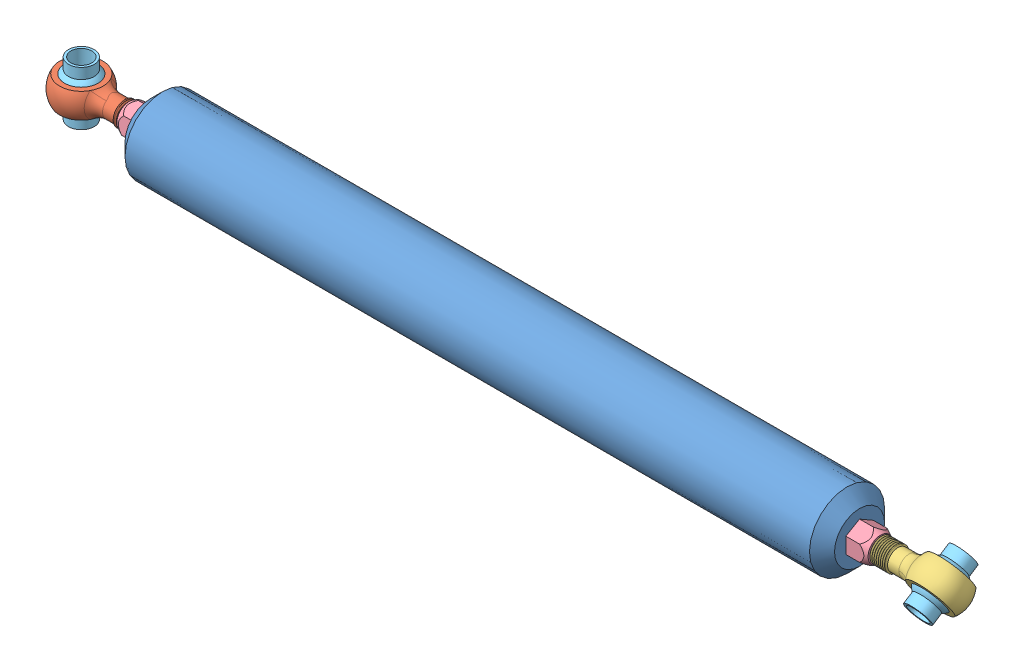
SolidWorks assembly Assem1, configuration Default. Lengths in mm.
Overall size (217.98 18 18).
7 component instances, 5 part files, 12 mates.
Components (placement in the parent):
- pushrod FS17-1: pushrod FS17 [Default] at (163.269 85.3777 125.7773) size (170.63 18 18)
- Pushrod screw-1: Pushrod screw [Default] at (-23.1854 85.3777 125.7773) size (36.78 6.57 12)
- screw bottom Pushrod-1: screw bottom Pushrod [Default] at (182.7233 85.3777 125.7773) x (-1 0 0) z (0 0.837559 0.546346) size (36.78 6.57 12)
- clockwise nut-1: clockwise nut [Default] at (-6.731 85.3777 125.7773) x (-1 0 0) z (0 -0.924225 -0.381849) size (9 8.1 6.58)
- clockwise nut-2: clockwise nut [Default] at (163.269 85.3777 125.7773) size (9 8.1 6.58)
- J1-1: J1 [Default] at (-23.1854 78.9073 125.7773) size (10 12.94 10)
- J1-2: J1 [Default] at (182.7233 81.8426 131.1966) x (-0.969411 -0.205574 -0.134098) z (0.245445 -0.811939 -0.529634) size (10 12.94 10)
Mates (geometry in assembly coordinates):
- Distance1: distance = 10 mm anti-aligned: plane of pushrod FS17-1 through (17.269 85.3777 125.7773) normal (-1 0 0); plane of Pushrod screw-1 through (7.269 85.3777 125.7773) normal (1 0 0)
- Coincident2: coincident anti-aligned: axis of pushrod FS17-1 through (17.269 85.3777 125.7773) axis (-1 0 0); line of Pushrod screw-1 through (-23.1854 85.3777 125.7773) axis (1 0 0)
- Distance2: distance = 13 mm anti-aligned: plane of screw bottom Pushrod-1 through (152.269 85.3777 125.7773) normal (-1 0 0); plane of pushrod FS17-1 through (139.269 85.3777 125.7773) normal (1 0 0)
- Coincident4: coincident aligned: axis of pushrod FS17-1 through (139.269 85.3777 125.7773) axis (1 0 0); line of screw bottom Pushrod-1 through (152.269 85.3777 125.7773) axis (1 0 0)
- Coincident5: coincident anti-aligned: line of Pushrod screw-1 through (-23.1854 85.3777 125.7773) axis (1 0 0); line of clockwise nut-1 through (-6.731 85.3777 125.7773) axis (-1 0 0)
- Coincident6: coincident anti-aligned: plane of pushrod FS17-1 through (-6.731 85.3777 125.7773) normal (-1 0 0); plane of clockwise nut-1 through (-6.731 85.3777 125.7773) normal (1 0 0)
- Coincident7: coincident aligned: line of screw bottom Pushrod-1 through (152.269 85.3777 125.7773) axis (1 0 0); line of clockwise nut-2 through (163.269 85.3777 125.7773) axis (1 0 0)
- Coincident8: coincident anti-aligned: plane of pushrod FS17-1 through (163.269 85.3777 125.7773) normal (1 0 0); plane of clockwise nut-2 through (163.269 85.3777 125.7773) normal (-1 0 0)
- Coincident9: coincident aligned: axis of Pushrod screw-1 through (-23.1854 88.4501 125.7773) axis (0 -1 0); axis of J1-1 through (-23.1854 88.6152 125.7773) axis (0 -1 0)
- Concentric1: concentric: sphere of Pushrod screw-1; sphere of J1-1
- Coincident10: coincident aligned: axis of screw bottom Pushrod-1 through (182.7233 83.699 128.3507) axis (0 0.546346 -0.837559); axis of J1-2 through (182.7233 81.8426 131.1966) axis (0 0.546346 -0.837559)
- Concentric2: concentric: sphere of screw bottom Pushrod-1; sphere of J1-2
